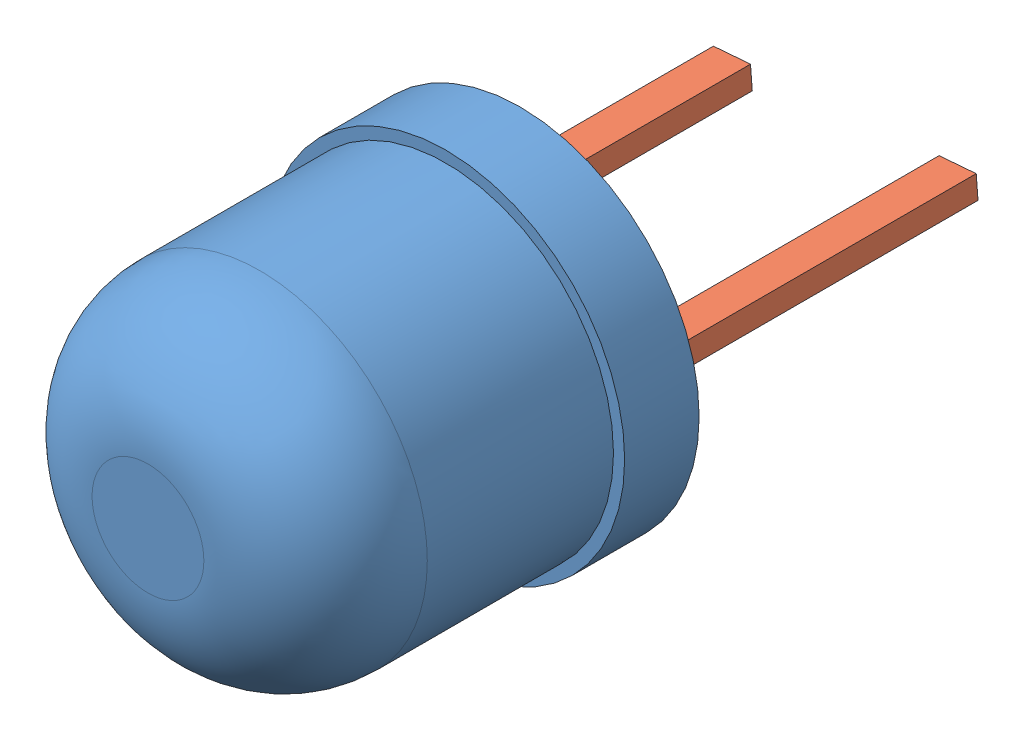
SolidWorks assembly LED, configuration По умолчанию. Lengths in mm.
Overall size (4.8 4.8 9.41).
2 component instances, 2 part files, 2 mates.
Components (placement in the parent):
- LED_BASE-1: LED_BASE [По умолчанию] at (-0.4898 -4.9377 3.5) size (4.8 4.8 5)
- LED_LEGS_2.54-1: LED_LEGS_2.54 [По умолчанию] at (74.5091 5.8507 -1.9071) x (0.996825 0.079623 0) z (0 0 1) size (3.54 0.3 4.41)
Mates (geometry in assembly coordinates):
- Совпадение1: coincident: plane of LED_BASE-1 through (-0.4898 0.0193 2.5) normal (0 0 -1); line of LED_LEGS_2.54-1 through (0.748 -0.0411 2.5) axis (0.996825 0.079623 0)
- Параллельность1: parallel anti-aligned: plane of LED_BASE-1 through (-0.4898 0.0193 2.5) normal (0 0 -1); plane of LED_LEGS_2.54-1 through (1.2225 0.2978 2.5) normal (0 0 1)
